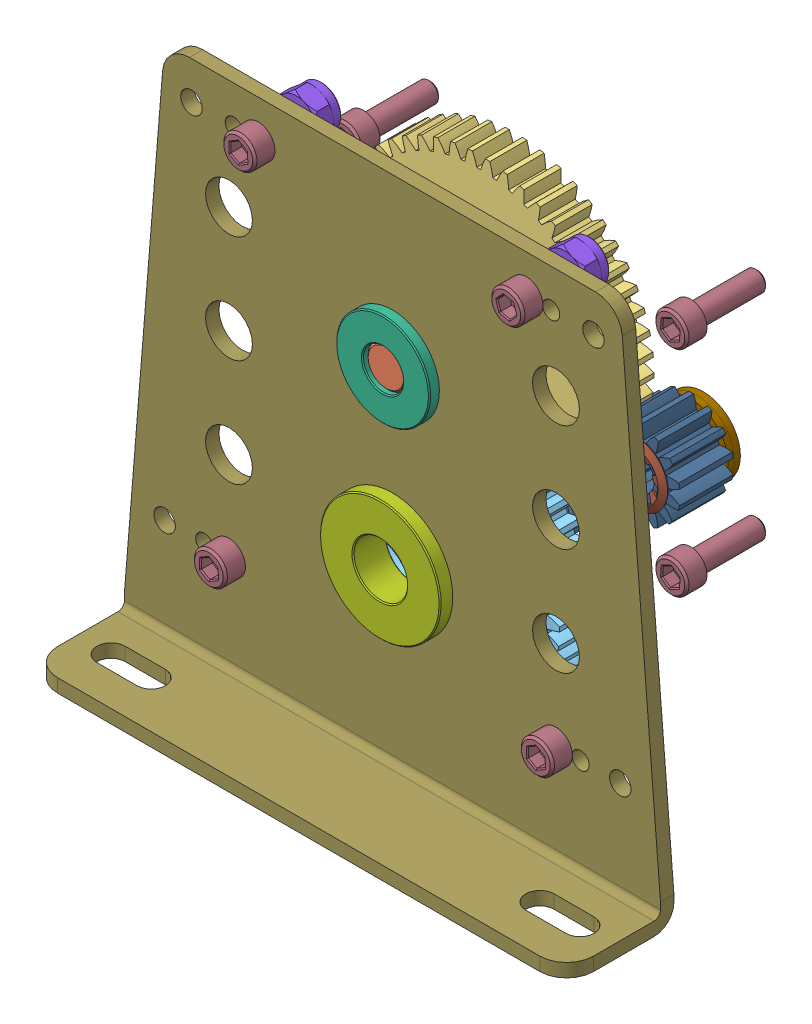
SolidWorks assembly DRIVE Toughbox Mini Gearbox, configuration Default. Lengths in mm.
Overall size (127 129.02 69.98).
29 component instances, 13 part files, 2 mates.
Components (placement in the parent):
- r6zz-1: r6zz [Default] at (0 40.7162 8.636) x (0.923728 0.383049 0) z (0 0 -1) size (22.23 22.23 7.11)
- r6zz-2: r6zz [Default] at (0 0 8.636) x (0.923728 0.383049 0) z (0 0 -1) size (22.23 22.23 7.11)
- Toughbox_d07-1: Toughbox_d07 [Default] at (28.1116 8.6845 34.163) x (0.901009 -0.433799 0) z (-0.433799 -0.901009 0) size (11 38.23 9.52)
- Toughbox_d05-1: Toughbox_d05 [Default] at (0 40.7162 18.796) x (0.901009 -0.433799 0) z (0 0 -1) size (65.97 66.04 10.34)
- Toughbox_d08-1: Toughbox_d08 [Default] at (0 40.7162 18.796) x (0.901009 -0.433799 0) z (0 0 1) size (20.03 20.32 15.25)
- Toughbox_d06-1: Toughbox_d06 [Default] at (0 0 23.4188) x (0.956002 0.293359 0) z (0 0 1) size (65.97 66.04 10.62)
- fr-6-zz-1: fr-6-zz [Default] at (7.4226 32.9743 34.163) x (0.97844 -0.20653 0) z (0 0 1) size (24.69 24.69 7.16)
- fr-8-zz-1: fr-8-zz [Default] at (7.4226 -7.7419 34.036) x (0.97844 -0.20653 0) z (0 0 1) size (31.75 31.75 7.95)
- 10-32_nylock_nut-1: 10-32_nylock_nut [Default] at (140.5562 -27.1657 -65.5923) x (-0.970695 0.240315 0) z (0 0 1) size (11.98 11.69 7.5)
- 10-32_nylock_nut-2: 10-32_nylock_nut [Default] at (63.0862 -27.1657 -65.5923) x (-0.970695 0.240315 0) z (0 0 1) size (11.98 11.69 7.5)
- 10-32_nylock_nut-3: 10-32_nylock_nut [Default] at (70.0712 61.7343 -65.5923) x (-0.970695 0.240315 0) z (0 0 1) size (11.98 11.69 7.5)
- 10-32_nylock_nut-4: 10-32_nylock_nut [Default] at (133.5712 61.7343 -65.5923) x (-0.970695 0.240315 0) z (0 0 1) size (11.98 11.69 7.5)
- 5-16_washer-1: 5-16_washer [Default] at (38.735 28.1699 5.5372) x (0.38418 -0.923258 0) z (0 0 -1) size (17.53 17.53 1.47)
- 5-16_washer-2: 5-16_washer [Default] at (38.735 28.1699 7.0104) x (0.897267 -0.441488 0) z (0 0 -1) size (17.53 17.53 1.47)
- 5-16_washer-3: 5-16_washer [Default] at (-38.735 28.1699 5.5372) x (-0.990116 0.140253 0) z (0 0 1) size (17.53 17.53 1.47)
- 5-16_washer-4: 5-16_washer [Default] at (-38.735 28.1699 4.064) x (-0.681761 0.731575 0) z (0 0 1) size (17.53 17.53 1.47)
- Toughbox_d09-1: Toughbox_d09 [Default] at (38.735 28.1699 19.7104) x (0.897267 -0.441488 0) z (0 0 -1) size (20.03 20.32 12.7)
- Toughbox_d09-2: Toughbox_d09 [Default] at (-38.735 28.1699 19.7104) x (-0.994128 0.108207 0) z (0 0 -1) size (20.03 20.32 12.7)
- 8mm_spring_clip-1: 8mm_spring_clip [Default] at (38.735 28.1699 20.6508) x (0 0 -1) z (0.163192 0.986594 0) size (1.12 14.83 14.83)
- 8mm_spring_clip-2: 8mm_spring_clip [Default] at (-38.735 28.1699 20.6508) x (0 0 -1) z (0.99913 0.041715 0) size (1.12 14.83 14.83)
- Toughbox-mini_d02-1: Toughbox-mini_d02 [Default] at (0 19.2532 38.989) x (-1 0 0) z (0 0 -1) size (127 123.82 25.4)
- 10-32x0625_shcs-1: 10-32x0625_shcs [Default] at (38.735 53.5699 11.8872) x (-0.564778 -0.825243 0) z (-0.825243 0.564778 0) size (7.82 20.65 7.82)
- 10-32x0625_shcs-2: 10-32x0625_shcs [Default] at (-31.75 70.5879 43.7642) x (0.507484 -0.861661 0) z (-0.861661 -0.507484 0) size (7.82 20.65 7.82)
- 10-32x0625_shcs-3: 10-32x0625_shcs [Default] at (-38.735 -18.3121 43.7642) x (0.507484 -0.861661 0) z (-0.861661 -0.507484 0) size (7.82 20.65 7.82)
- 10-32x0625_shcs-4: 10-32x0625_shcs [Default] at (38.735 -18.3121 43.7642) x (0.507484 -0.861661 0) z (-0.861661 -0.507484 0) size (7.82 20.65 7.82)
- 10-32x0625_shcs-5: 10-32x0625_shcs [Default] at (31.75 70.5879 43.7642) x (0.740711 -0.671824 0) z (-0.671824 -0.740711 0) size (7.82 20.65 7.82)
- 10-32x0625_shcs-6: 10-32x0625_shcs [Default] at (38.735 2.7699 11.8872) x (-0.564778 -0.825243 0) z (-0.825243 0.564778 0) size (7.82 20.65 7.82)
- 10-32x0625_shcs-7: 10-32x0625_shcs [Default] at (-38.735 53.5699 11.8872) x (-0.966277 -0.257503 0) z (-0.257503 0.966277 0) size (7.82 20.65 7.82)
- 10-32x0625_shcs-8: 10-32x0625_shcs [Default] at (-38.735 2.7699 11.8872) x (-0.99652 0.083357 0) z (0.083357 0.99652 0) size (7.82 20.65 7.82)
Mates (geometry in assembly coordinates):
- Concentric6: concentric anti-aligned: cylinder of fr-8-zz-1 through (0 0 41.9862) axis (0 0 -1) radius 14.2875; cylinder of Toughbox-mini_d02-1 through (0 0 211.0153) axis (0 0 1) radius 14.2812
- Concentric7: concentric anti-aligned: cylinder of fr-6-zz-1 through (0 40.7162 41.3258) axis (0 0 -1) radius 11.1125; cylinder of Toughbox-mini_d02-1 through (0 40.7162 211.0153) axis (0 0 1) radius 11.1061
